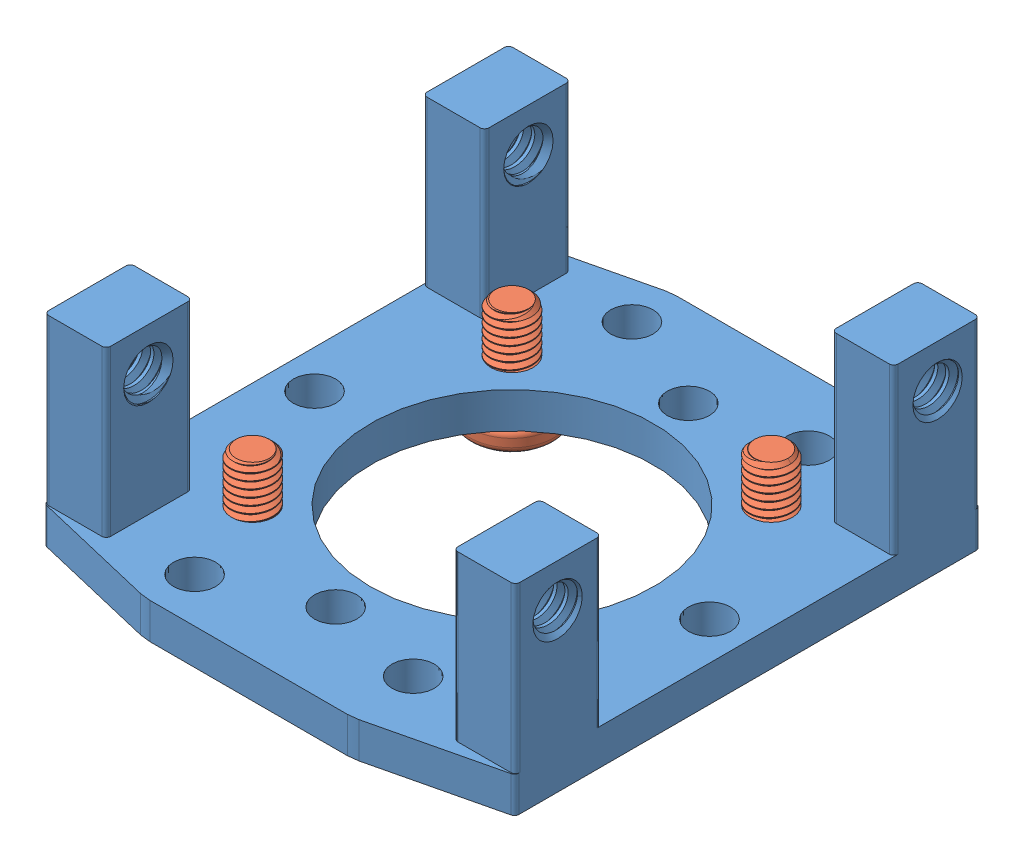
SolidWorks assembly 555188 assembly, configuration Default. Lengths in mm.
Overall size (33.64 16.62 37.36).
5 component instances, 2 part files, 0 mates.
Components (placement in the parent):
- 555188-1: 555188 [Default] at (-6.4793 1.7739 -2.6152) size (33.64 14.22 37.36)
- 555188 screw_92005A116-1: 555188 screw_92005A116 [Default] at (-15.6717 7.7739 6.5772) x (1 0 0) z (0 -1 0) size (6 6 8.48)
- 555188 screw_92005A116-2: 555188 screw_92005A116 [Default] at (2.7131 7.7739 6.5772) x (0 0 -1) z (0 -1 0) size (6 6 8.48)
- 555188 screw_92005A116-3: 555188 screw_92005A116 [Default] at (2.7131 7.7739 -11.8076) x (-1 0 0) z (0 -1 0) size (6 6 8.48)
- 555188 screw_92005A116-4: 555188 screw_92005A116 [Default] at (-15.6717 7.7739 -11.8076) x (0 0 1) z (0 -1 0) size (6 6 8.48)
